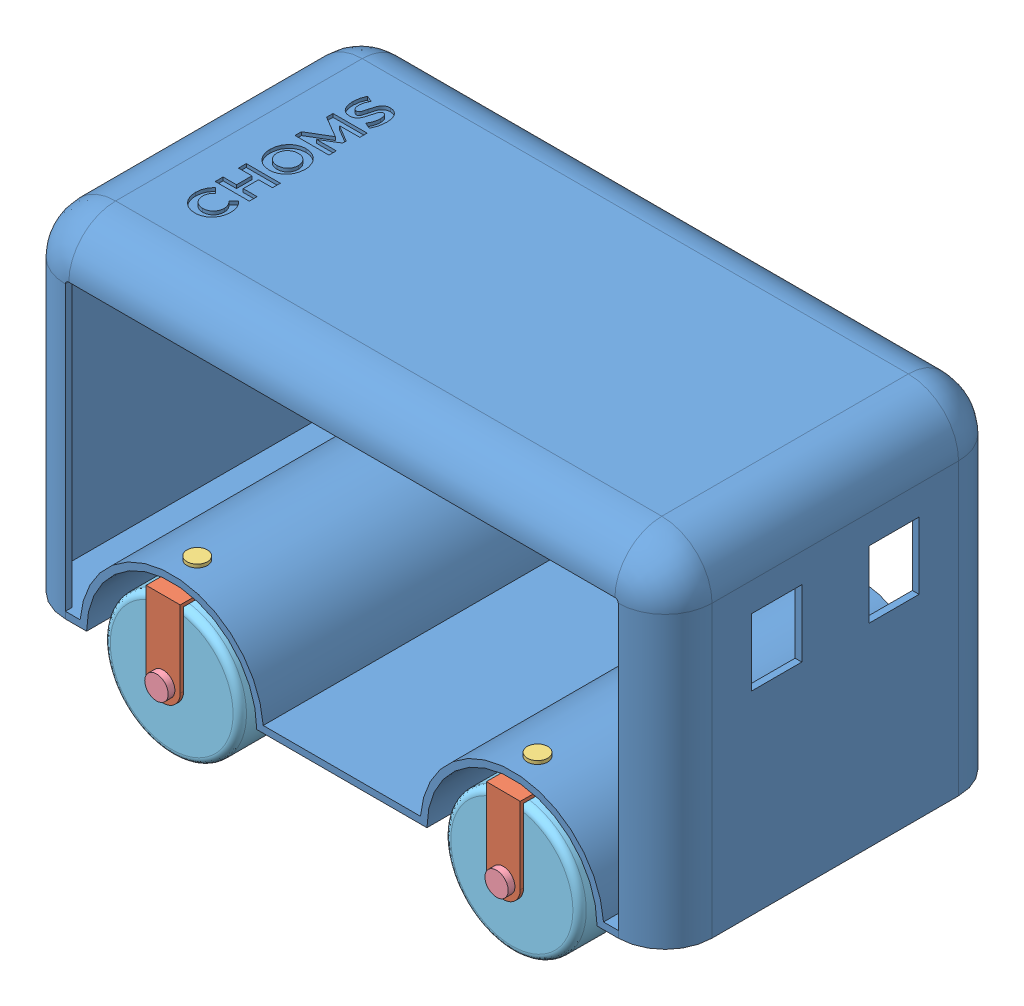
SolidWorks assembly FinalAssem4, configuration Default. Lengths in mm.
Overall size (965.2 647.74 554.88).
21 component instances, 5 part files, 18 mates.
Components (placement in the parent):
- BODY-1: BODY [Default] at (355.0397 333.1063 686.9716) size (965.2 508 508)
- Assem1-1: Assem1 [Default] at (150.2541 268.4552 979.3371) x (-1 0 0) z (0 0 -1) size (50.8 165.1 121.6)
  - 1-1: 1 [Default] at (49.2145 66.9511 76.4655) size (50.8 139.7 101.6)
  - wheelhinge-1: wheelhinge [Default] at (49.2145 188.9511 76.4655) x (0.436076 0 -0.89991) z (0.89991 0 0.436076) size (30.48 35.4 30.48)
  - tyrepin-1: tyrepin [Default] at (49.2145 66.9511 76.4655) x (0.587335 0.809344 0) z (0 0 1) size (35 35 121.6)
- Assem1-2: Assem1 [Default] at (560.2818 268.4552 826.1141) x (0.999982 0 0.005959) z (-0.005959 0 0.999982) size (50.8 165.1 121.6)
  - 1-1: 1 [Default] at (49.2145 66.9511 76.4655) size (50.8 139.7 101.6)
  - wheelhinge-1: wheelhinge [Default] at (49.2145 188.9511 76.4655) x (0.436076 0 -0.89991) z (0.89991 0 0.436076) size (30.48 35.4 30.48)
  - tyrepin-1: tyrepin [Default] at (49.2145 66.9511 76.4655) x (0.587335 0.809344 0) z (0 0 1) size (35 35 121.6)
- Assem1-3: Assem1 [Default] at (51.8252 268.4552 394.606) size (50.8 165.1 121.6)
  - 1-1: 1 [Default] at (49.2145 66.9511 76.4655) size (50.8 139.7 101.6)
  - wheelhinge-1: wheelhinge [Default] at (49.2145 188.9511 76.4655) x (0.436076 0 -0.89991) z (0.89991 0 0.436076) size (30.48 35.4 30.48)
  - tyrepin-1: tyrepin [Default] at (49.2145 66.9511 76.4655) x (0.587335 0.809344 0) z (0 0 1) size (35 35 121.6)
- Assem1-4: Assem1 [Default] at (564.2076 268.4552 391.9569) x (0.998414 0 0.056291) z (-0.056291 0 0.998414) size (50.8 165.1 121.6)
  - 1-1: 1 [Default] at (49.2145 66.9511 76.4655) size (50.8 139.7 101.6)
  - wheelhinge-1: wheelhinge [Default] at (49.2145 188.9511 76.4655) x (0.436076 0 -0.89991) z (0.89991 0 0.436076) size (30.48 35.4 30.48)
  - tyrepin-1: tyrepin [Default] at (49.2145 66.9511 76.4655) x (0.587335 0.809344 0) z (0 0 1) size (35 35 121.6)
- tyre-1: tyre [Default] at (609.0397 335.4063 471.0716) x (-0.175271 -0.984471 -0.009882) z (-0.056291 0 0.998414) size (203.2 203.2 76.2)
- tyre-2: tyre [Default] at (609.0397 335.4063 902.8716) x (0.950972 0.309224 0.005667) z (-0.005959 0 0.999982) size (203.2 203.2 76.2)
- tyre-3: tyre [Default] at (101.0397 335.4063 471.0716) x (-0.805563 -0.592511 0) z (0 0 1) size (203.2 203.2 76.2)
- tyre-4: tyre [Default] at (101.0397 335.4063 902.8716) x (-0.530667 -0.84758 0) z (0 0 1) size (203.2 203.2 76.2)
Mates (geometry in assembly coordinates):
- Concentric1: concentric anti-aligned: cylinder of BODY-1 through (101.0397 366.1063 902.8716) axis (0 1 0) radius 12.7; cylinder of Assem1-1/wheelhinge-1 through (101.0397 470.1063 902.8716) axis (0 -1 0) radius 12.7
- Tangent1: tangent anti-aligned: cylinder of BODY-1 through (101.0397 333.1063 940.9716) axis (0 0 -1) radius 137; plane of Assem1-1/wheelhinge-1 through (101.0397 470.1063 902.8716) normal (0 -1 0)
- Concentric2: concentric anti-aligned: cylinder of BODY-1 through (609.0397 366.1063 902.8716) axis (0 1 0) radius 12.7; cylinder of Assem1-2/wheelhinge-1 through (609.0397 470.1063 902.8716) axis (0 -1 0) radius 12.7
- Tangent2: tangent anti-aligned: cylinder of BODY-1 through (609.0397 333.1063 940.9716) axis (0 0 -1) radius 137; plane of Assem1-2/wheelhinge-1 through (609.0397 470.1063 902.8716) normal (0 -1 0)
- Concentric3: concentric anti-aligned: cylinder of BODY-1 through (101.0397 366.1063 471.0716) axis (0 1 0) radius 12.7; cylinder of Assem1-3/wheelhinge-1 through (101.0397 470.1063 471.0716) axis (0 -1 0) radius 12.7
- Tangent3: tangent anti-aligned: cylinder of BODY-1 through (101.0397 333.1063 940.9716) axis (0 0 -1) radius 137; plane of Assem1-3/wheelhinge-1 through (101.0397 470.1063 471.0716) normal (0 -1 0)
- Concentric4: concentric anti-aligned: cylinder of BODY-1 through (609.0397 366.1063 471.0716) axis (0 1 0) radius 12.7; cylinder of Assem1-4/wheelhinge-1 through (609.0397 470.1063 471.0716) axis (0 -1 0) radius 12.7
- Tangent4: tangent anti-aligned: cylinder of BODY-1 through (609.0397 333.1063 940.9716) axis (0 0 -1) radius 137; plane of Assem1-4/wheelhinge-1 through (609.0397 470.1063 471.0716) normal (0 -1 0)
- Parallel2: parallel aligned: plane of BODY-1 through (762.6397 766.1063 432.9716) normal (0 0 -1); plane of Assem1-3/tyrepin-1 through (101.0397 335.4063 410.2716) normal (0 0 -1)
- Parallel3: parallel aligned: plane of BODY-1 through (762.6397 766.1063 940.9716) normal (0 0 1); plane of Assem1-1/tyrepin-1 through (101.0397 335.4063 963.6716) normal (0 0 1)
- Concentric5: concentric aligned: cylinder of Assem1-4/tyrepin-1 through (606.6039 335.4063 521.8132) axis (0.047948 0 -0.99885) radius 12.7; cylinder of tyre-1 through (607.2128 335.4063 509.1278) axis (0.047948 0 -0.99885) radius 12.7
- Width1: width anti-aligned: plane of tyre-1 through (610.8665 335.4063 433.0154) normal (0.047948 0 -0.99885); plane of tyre-1 through (607.2128 335.4063 509.1278) normal (-0.047948 0 0.99885); plane of Assem1-4/1-1 through (535.1233 444.7063 421.6706) normal (-0.047948 0 0.99885); plane of Assem1-4/1-1 through (530.7313 444.7063 513.1652) normal (0.047948 0 -0.99885)
- Concentric6: concentric aligned: cylinder of Assem1-2/tyrepin-1 through (608.7369 335.4063 953.6707) axis (0.005959 0 -0.999982) radius 12.7; cylinder of tyre-2 through (608.8126 335.4063 940.9709) axis (0.005959 0 -0.999982) radius 12.7
- Width2: width anti-aligned: plane of tyre-2 through (608.8126 335.4063 940.9709) normal (-0.005959 0 0.999982); plane of tyre-2 through (609.2667 335.4063 864.7723) normal (0.005959 0 -0.999982); plane of Assem1-2/1-1 through (532.5681 444.7063 948.2167) normal (0.005959 0 -0.999982); plane of Assem1-2/1-1 through (533.1139 444.7063 856.6183) normal (-0.005959 0 0.999982)
- Concentric7: concentric aligned: cylinder of Assem1-3/tyrepin-1 through (101.0397 335.4063 521.8716) axis (0 0 -1) radius 12.7; cylinder of tyre-3 through (101.0397 335.4063 509.1716) axis (0 0 -1) radius 12.7
- Width3: width anti-aligned: plane of tyre-3 through (101.0397 335.4063 432.9716) normal (0 0 -1); plane of tyre-3 through (101.0397 335.4063 509.1716) normal (0 0 1); plane of Assem1-3/1-1 through (24.8397 444.7063 425.2716) normal (0 0 1); plane of Assem1-3/1-1 through (24.8397 444.7063 516.8716) normal (0 0 -1)
- Width4: width anti-aligned: plane of tyre-4 through (101.0397 335.4063 940.9716) normal (0 0 1); plane of tyre-4 through (101.0397 335.4063 864.7716) normal (0 0 -1); plane of Assem1-1/1-1 through (177.2397 444.7063 948.6716) normal (0 0 -1); plane of Assem1-1/1-1 through (177.2397 444.7063 857.0716) normal (0 0 1)
- Concentric8: concentric anti-aligned: cylinder of Assem1-1/tyrepin-1 through (101.0397 335.4063 852.0716) axis (0 0 1) radius 12.7; cylinder of tyre-4 through (101.0397 335.4063 940.9716) axis (0 0 -1) radius 12.7
